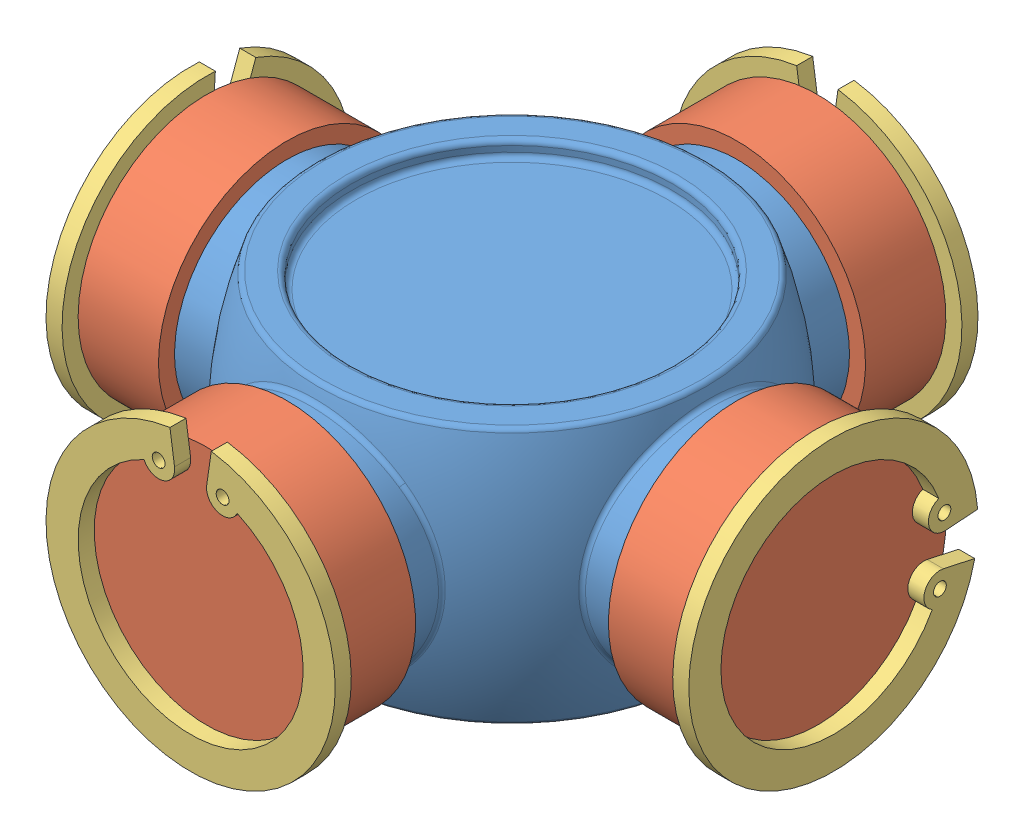
SolidWorks assembly Assemblage1, configuration Défaut. Lengths in mm.
Overall size (31.75 17.28 31.75).
9 component instances, 3 part files, 16 mates.
Components (placement in the parent):
- croix-1: croix [Défaut] at origin size (28.57 12.7 28.57)
- coussinet-1: coussinet [Défaut] at (-8.501 0 0) x (0 0.97948 0.20154) z (-1 0 0) size (12.7 12.7 3.97)
- coussinet-2: coussinet [Défaut] at (-0.0002 0 -8.5008) x (0.94577 -0.324837 0) z (0 0 -1) size (12.7 12.7 3.97)
- coussinet-3: coussinet [Défaut] at (-0.0002 0 8.5008) size (12.7 12.7 3.97)
- coussinet-4: coussinet [Défaut] at (8.5006 0 0) x (0 -0.488169 -0.872749) z (1 0 0) size (12.7 12.7 3.97)
- snapring-1: snapring [Défaut] at (15.4779 -0.0149 -0.2115) x (0 -0.997523 0.070347) z (1 0 0) size (14.29 14.21 0.79)
- snapring-2: snapring [Défaut] at (-0.0002 0.212 -15.4781) size (14.29 14.21 0.79)
- snapring-3: snapring [Défaut] at (-0.0002 0.212 15.4781) size (14.29 14.21 0.79)
- snapring-4: snapring [Défaut] at (-15.4783 0.2076 -0.0428) x (0 -0.201908 -0.979404) z (1 0 0) size (14.29 14.21 0.79)
Mates (geometry in assembly coordinates):
- Coïncidente1: coincident: plane of croix-1 through (-0.0002 0 14.2875) normal (0 0 1); plane of coussinet-3 through (-0.0002 0 14.2875) normal (0 0 -1)
- Coaxiale1: concentric anti-aligned: cylinder of croix-1; cylinder of coussinet-3
- Coïncidente2: coincident: plane of coussinet-3 through (-0.0002 0 15.0813) normal (0 0 1); plane of snapring-3 through (-0.0002 0 15.0813) normal (0 0 -1)
- Coaxiale2: concentric aligned: cylinder of coussinet-3; cylinder of snapring-3
- Coïncidente3: coincident: plane of croix-1 through (0 -14.2877 0) normal (0 -1 0); plane of coussinet-1 through (0 -14.2877 0) normal (0 1 0)
- Coaxiale3: concentric anti-aligned: cylinder of croix-1; cylinder of coussinet-1
- Coïncidente4: coincident: plane of croix-1 through (-0.0002 0 -14.2875) normal (0 0 -1); plane of coussinet-2 through (-0.0002 0 -14.2875) normal (0 0 1)
- Coaxiale4: concentric anti-aligned: cylinder of croix-1; cylinder of coussinet-2
- Coïncidente5: coincident: plane of coussinet-2 through (-0.0002 0 -15.0812) normal (0 0 -1); plane of snapring-2 through (-0.0002 0 -15.0812) normal (0 0 1)
- Coaxiale5: concentric anti-aligned: cylinder of coussinet-2; cylinder of snapring-2
- Coïncidente6: coincident: plane of coussinet-1 through (0 -15.0815 0) normal (0 -1 0); plane of snapring-4 through (0 -15.0815 0) normal (0 1 0)
- Coaxiale6: concentric anti-aligned: cylinder of coussinet-1; cylinder of snapring-4
- Coïncidente7: coincident: plane of croix-1 through (0 14.2873 0) normal (0 1 0); plane of coussinet-4 through (0 14.2873 0) normal (0 -1 0)
- Coaxiale7: concentric anti-aligned: cylinder of croix-1; cylinder of coussinet-4
- Coïncidente8: coincident: plane of coussinet-4 through (0 15.081 0) normal (0 1 0); plane of ? through (15.081 14.7099 6.3617) normal (-1 0 0)
- Coaxiale8: concentric aligned: cylinder of coussinet-4; cylinder of ?
